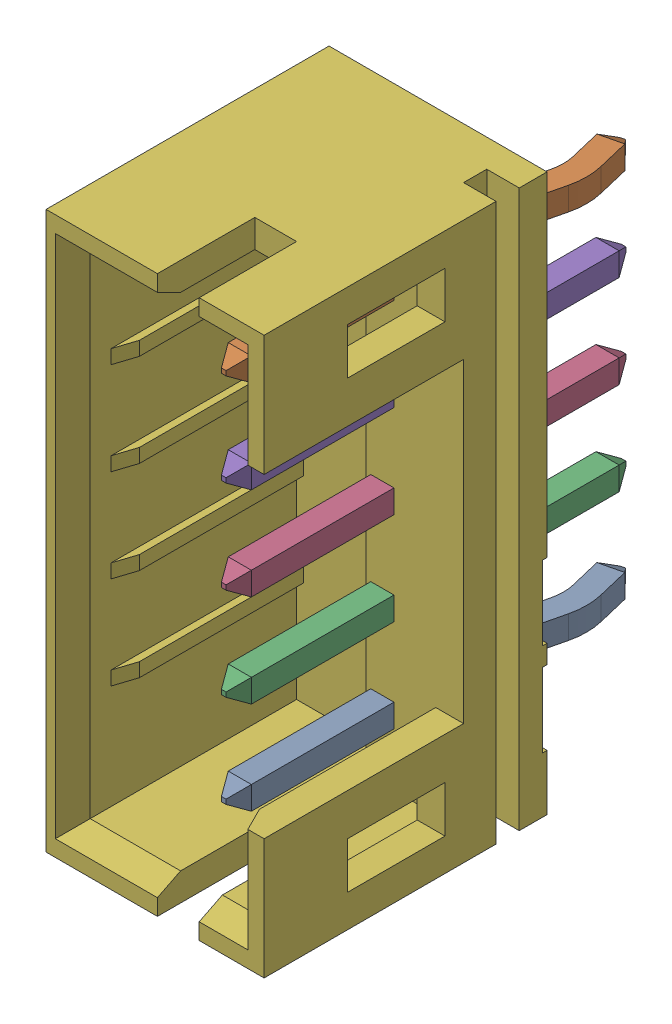
SolidWorks assembly J3, configuration Default. Lengths in mm.
Overall size (4.7 12 9.5).
7 component instances, 3 part files, 0 mates.
Components (placement in the parent):
- 62000511622-1: 62000511622 [Default] at (19.99 13.0555 3.1) x (0 1 0) z (0 0 1) size (12 4.7 9.5)
  - Pin1-1: Pin1 [Default] at (-4 -0.35 -3.88) x (0 1 0) z (0 0 1) size (0.77 0.5 8.62)
  - Pin1-2: Pin1 [Default] at (4 -0.35 -3.88) x (0 1 0) z (0 0 1) size (0.77 0.5 8.62)
  - Pin2-1: Pin2 [Default] at (-2 -0.85 -6.45) x (0 -1 0) z (0 0 1) size (0.5 0.5 8.62)
  - Pin2-2: Pin2 [Default] at (0 -0.85 -6.45) x (0 -1 0) z (0 0 1) size (0.5 0.5 8.62)
  - Pin2-3: Pin2 [Default] at (2 -0.85 -6.45) x (0 -1 0) z (0 0 1) size (0.5 0.5 8.62)
  - 62000511622-1: 62000511622 [Default] at origin size (12 4.7 6.1)
